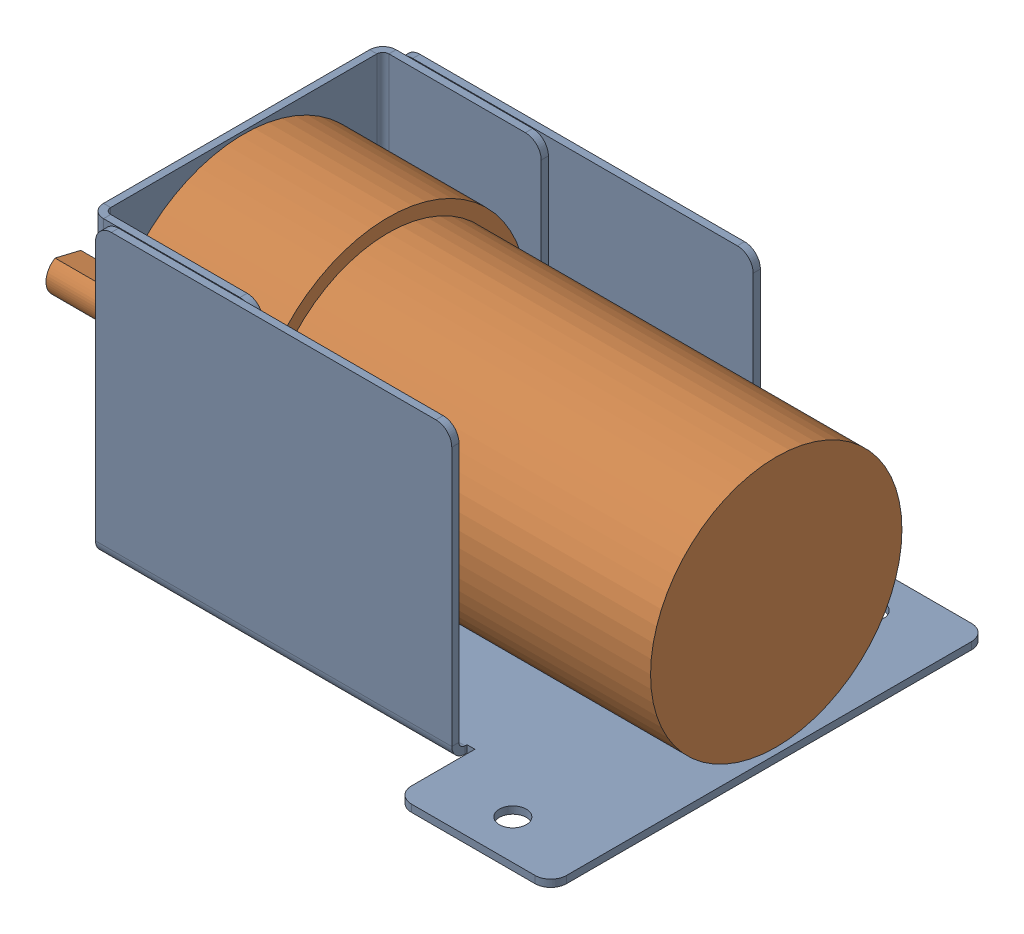
SolidWorks assembly MirrorBarbCole Motor with Fixture, configuration Default. Lengths in mm.
Overall size (89.87 36.41 55.14).
2 component instances, 2 part files, 2 mates.
Components (placement in the parent):
- MirrorBarbCole Geared Fixture-1: MirrorBarbCole Geared Fixture [Default] at (-41.6291 -27.9181 -27.027) size (67.26 36.41 55.14)
- MirrorMotor BarbCole Geared-1: MirrorMotor BarbCole Geared [Default] at (-22.4819 -10.3495 -9.4562) size (89.87 35.14 35.14)
Mates (geometry in assembly coordinates):
- Concentric1: concentric aligned: circle of MirrorBarbCole Geared Fixture-1; circle of MirrorMotor BarbCole Geared-1
- Coincident1: coincident anti-aligned: plane of MirrorBarbCole Geared Fixture-1 through (-40.7191 -27.9181 -27.027) normal (1 0 0); plane of MirrorMotor BarbCole Geared-1 through (-40.7191 -10.3495 -9.4562) normal (-1 0 0)
